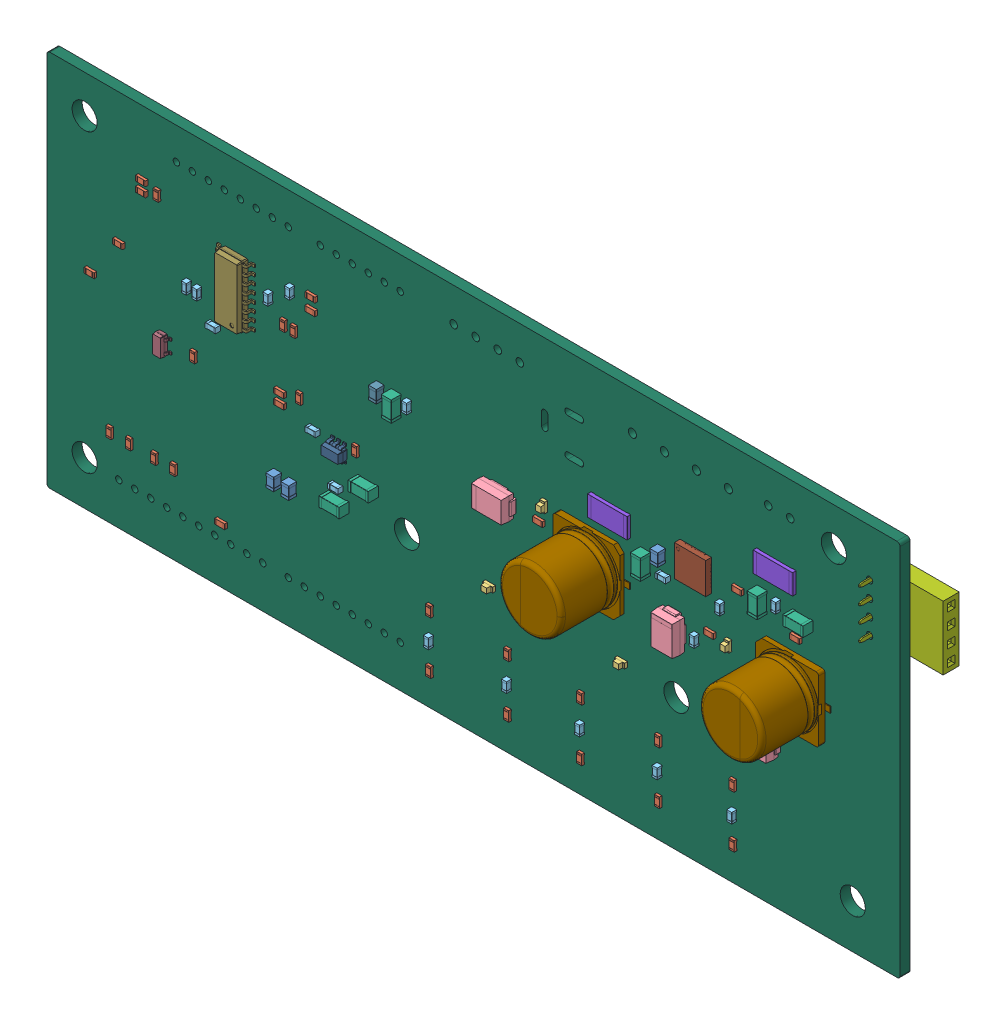
SolidWorks assembly MMTK - For Test Bed v1.5.step, configuration Default. Lengths in mm.
Overall size (140.71 60 14.24).
155 component instances, 15 part files, 0 mates.
Components (placement in the parent):
- C_0805_2012Metric.step-1: C_0805_2012Metric.step [Default] at (39.0906 -40.4144 1.65) x (0 1 0) z (0 0 1) size (2 1.25 1.25)
  - SOLID.step-1: SOLID.step [Default] at origin size (2 1.25 1.25)
- C_0805_2012Metric.step-2: C_0805_2012Metric.step [Default] at (36.6903 -40.4114 1.65) x (0 1 0) z (0 0 1) size (2 1.25 1.25)
  - SOLID.step-1: SOLID.step [Default] at origin size (2 1.25 1.25)
- R_0603_1608Metric.step-1: R_0603_1608Metric.step [Default] at (37.3126 -29.7815 1.65) size (1.6 0.8 0.45)
  - SOLID-0.step-1: SOLID-0.step [Default] at origin size (1.6 0.8 0.45)
- R_0603_1608Metric.step-2: R_0603_1608Metric.step [Default] at (37.3126 -28.2321 1.65) size (1.6 0.8 0.45)
  - SOLID-0.step-1: SOLID-0.step [Default] at origin size (1.6 0.8 0.45)
- R_0603_1608Metric.step-3: R_0603_1608Metric.step [Default] at (78.4097 -25.4 1.65) x (-1 0 0) z (0 0 1) size (1.6 0.8 0.45)
  - SOLID-0.step-1: SOLID-0.step [Default] at origin size (1.6 0.8 0.45)
- LED_0603_1608Metric.step-1: LED_0603_1608Metric.step [Default] at (79.1972 -22.8853 1.65) x (0 1 0) z (0 0 1) size (1.6 0.8 1.1)
  - SOLID-1.step-1: SOLID-1.step [Default] at origin size (1.6 0.8 1.1)
- R_0603_1608Metric.step-4: R_0603_1608Metric.step [Default] at (23.5585 -30.1245 1.65) x (0 1 0) z (0 0 1) size (1.6 0.8 0.45)
  - SOLID-0.step-1: SOLID-0.step [Default] at origin size (1.6 0.8 0.45)
- D_SMB.step-1: D_SMB.step [Default] at (114.046 -37.084 1.65) size (5.3 3.55 2.15)
  - SOLID-2.step-1: SOLID-2.step [Default] at origin size (5.3 3.55 2.15)
- R_0603_1608Metric.step-5: R_0603_1608Metric.step [Default] at (7.2 -26.775 1.65) size (1.6 0.8 0.45)
  - SOLID-0.step-1: SOLID-0.step [Default] at origin size (1.6 0.8 0.45)
- R_0603_1608Metric.step-6: R_0603_1608Metric.step [Default] at (11.7125 -20.525 1.65) x (-1 0 0) z (0 0 1) size (1.6 0.8 0.45)
  - SOLID-0.step-1: SOLID-0.step [Default] at origin size (1.6 0.8 0.45)
- LED_0603_1608Metric.step-2: LED_0603_1608Metric.step [Default] at (70.55 -38.3 1.65) x (-1 0 0) z (0 0 1) size (1.6 0.8 1.1)
  - SOLID-1.step-1: SOLID-1.step [Default] at origin size (1.6 0.8 1.1)
- R_0603_1608Metric.step-7: R_0603_1608Metric.step [Default] at (61.05 -46.3344 1.65) x (0 -1 0) z (0 0 1) size (1.6 0.8 0.45)
  - SOLID-0.step-1: SOLID-0.step [Default] at origin size (1.6 0.8 0.45)
- R_0603_1608Metric.step-8: R_0603_1608Metric.step [Default] at (109.225 -46.2125 1.65) x (0 -1 0) z (0 0 1) size (1.6 0.8 0.45)
  - SOLID-0.step-1: SOLID-0.step [Default] at origin size (1.6 0.8 0.45)
- R_0603_1608Metric.step-9: R_0603_1608Metric.step [Default] at (109.25 -54.4375 1.65) x (0 1 0) z (0 0 1) size (1.6 0.8 0.45)
  - SOLID-0.step-1: SOLID-0.step [Default] at origin size (1.6 0.8 0.45)
- C_0603_1608Metric.step-1: C_0603_1608Metric.step [Default] at (109.225 -50.3875 1.65) x (0 -1 0) z (0 0 1) size (1.6 0.8 0.8)
  - SOLID-3.step-1: SOLID-3.step [Default] at origin size (1.6 0.8 0.8)
- C_1206_3216Metric.step-1: C_1206_3216Metric.step [Default] at (120.145 -18.288 1.65) size (3.2 1.6 1.6)
  - SOLID-4.step-1: SOLID-4.step [Default] at origin size (3.2 1.6 1.6)
- PinSocket_1x04_P2.54mm_Horizontal.step-1: PinSocket_1x04_P2.54mm_Horizontal.step [Default] at (130.682 -7.5 -0.05) x (-1 0 0) z (0 0 -1) size (10.13 10.16 5.84)
  - SOLID-5.step-1: SOLID-5.step [Default] at origin size (10.13 10.16 5.84)
- R_2512_6332Metric.step-1: R_2512_6332Metric.step [Default] at (115.951 -13.589 1.65) size (6.3 3.2 0.6)
  - SOLID-6.step-1: SOLID-6.step [Default] at origin size (6.3 3.2 0.6)
- R_2512_6332Metric.step-2: R_2512_6332Metric.step [Default] at (89.65 -19.02 1.65) x (-1 0 0) z (0 0 1) size (6.3 3.2 0.6)
  - SOLID-6.step-1: SOLID-6.step [Default] at origin size (6.3 3.2 0.6)
- C_1206_3216Metric.step-2: C_1206_3216Metric.step [Default] at (113.665 -18.666 1.65) x (0 -1 0) z (0 0 1) size (3.2 1.6 1.6)
  - SOLID-4.step-1: SOLID-4.step [Default] at origin size (3.2 1.6 1.6)
- C_1206_3216Metric.step-3: C_1206_3216Metric.step [Default] at (95.13 -22.66 1.65) x (0 -1 0) z (0 0 1) size (3.2 1.6 1.6)
  - SOLID-4.step-1: SOLID-4.step [Default] at origin size (3.2 1.6 1.6)
- CP_Elec_10x10.step-1: CP_Elec_10x10.step [Default] at (86.753 -27.27 1.65) x (-1 0 0) z (0 0 1) size (13.47 13.66 10)
  - SOLID-7.step-1: SOLID-7.step [Default] at origin size (13.47 13.66 10)
- CP_Elec_10x10.step-2: CP_Elec_10x10.step [Default] at (118.618 -28.321 1.65) size (13.47 13.66 10)
  - SOLID-7.step-1: SOLID-7.step [Default] at origin size (13.47 13.66 10)
- SOT-23-6.step-1: SOT-23-6.step [Default] at (46.482 -31.58 1.65) x (0 1 0) z (0 0 1) size (2.8 2.9 1.55)
  - SOLID-8.step-1: SOLID-8.step [Default] at origin size (2.8 2.9 1.55)
- QFN-28-1EP_5x5mm_P0.5mm_EP3.35x3.35mm.step-1: QFN-28-1EP_5x5mm_P0.5mm_EP3.35x3.35mm.step [Default] at (103.132 -19.3635 1.65) size (5 5 0.92)
  - SOLID-9.step-1: SOLID-9.step [Default] at origin size (5 5 0.92)
- SOIC-16_3.9x9.9mm_P1.27mm.step-1: SOIC-16_3.9x9.9mm_P1.27mm.step [Default] at (30.226 -17.399 1.65) x (-1 0 0) z (0 0 1) size (6 9.9 1.75)
  - SOLID-10.step-1: SOLID-10.step [Default] at origin size (6 9.9 1.75)
- R_0603_1608Metric.step-10: R_0603_1608Metric.step [Default] at (10.2616 -47.1932 1.65) x (0 -1 0) z (0 0 1) size (1.6 0.8 0.45)
  - SOLID-0.step-1: SOLID-0.step [Default] at origin size (1.6 0.8 0.45)
- R_0603_1608Metric.step-11: R_0603_1608Metric.step [Default] at (13.3604 -47.1932 1.65) x (0 -1 0) z (0 0 1) size (1.6 0.8 0.45)
  - SOLID-0.step-1: SOLID-0.step [Default] at origin size (1.6 0.8 0.45)
- R_0603_1608Metric.step-12: R_0603_1608Metric.step [Default] at (17.3736 -47.1932 1.65) x (0 -1 0) z (0 0 1) size (1.6 0.8 0.45)
  - SOLID-0.step-1: SOLID-0.step [Default] at origin size (1.6 0.8 0.45)
- R_0603_1608Metric.step-13: R_0603_1608Metric.step [Default] at (20.4216 -47.1932 1.65) x (0 -1 0) z (0 0 1) size (1.6 0.8 0.45)
  - SOLID-0.step-1: SOLID-0.step [Default] at origin size (1.6 0.8 0.45)
- R_0603_1608Metric.step-14: R_0603_1608Metric.step [Default] at (61.05 -54.663 1.65) x (0 1 0) z (0 0 1) size (1.6 0.8 0.45)
  - SOLID-0.step-1: SOLID-0.step [Default] at origin size (1.6 0.8 0.45)
- R_0603_1608Metric.step-15: R_0603_1608Metric.step [Default] at (85.05 -54.6521 1.65) x (0 1 0) z (0 0 1) size (1.6 0.8 0.45)
  - SOLID-0.step-1: SOLID-0.step [Default] at origin size (1.6 0.8 0.45)
- R_0603_1608Metric.step-16: R_0603_1608Metric.step [Default] at (85.05 -46.3234 1.65) x (0 -1 0) z (0 0 1) size (1.6 0.8 0.45)
  - SOLID-0.step-1: SOLID-0.step [Default] at origin size (1.6 0.8 0.45)
- R_0603_1608Metric.step-17: R_0603_1608Metric.step [Default] at (73.45 -54.47 1.65) x (0 1 0) z (0 0 1) size (1.6 0.8 0.45)
  - SOLID-0.step-1: SOLID-0.step [Default] at origin size (1.6 0.8 0.45)
- R_0603_1608Metric.step-18: R_0603_1608Metric.step [Default] at (97.375 -54.3841 1.65) x (0 1 0) z (0 0 1) size (1.6 0.8 0.45)
  - SOLID-0.step-1: SOLID-0.step [Default] at origin size (1.6 0.8 0.45)
- R_0603_1608Metric.step-19: R_0603_1608Metric.step [Default] at (73.45 -46.1414 1.65) x (0 -1 0) z (0 0 1) size (1.6 0.8 0.45)
  - SOLID-0.step-1: SOLID-0.step [Default] at origin size (1.6 0.8 0.45)
- R_0603_1608Metric.step-20: R_0603_1608Metric.step [Default] at (97.375 -46.0555 1.65) x (0 -1 0) z (0 0 1) size (1.6 0.8 0.45)
  - SOLID-0.step-1: SOLID-0.step [Default] at origin size (1.6 0.8 0.45)
- R_0603_1608Metric.step-21: R_0603_1608Metric.step [Default] at (105.5371 -27.2288 1.65) x (-1 0 0) z (0 0 1) size (1.6 0.8 0.45)
  - SOLID-0.step-1: SOLID-0.step [Default] at origin size (1.6 0.8 0.45)
- R_0603_1608Metric.step-22: R_0603_1608Metric.step [Default] at (119.2275 -21.082 1.65) x (-1 0 0) z (0 0 1) size (1.6 0.8 0.45)
  - SOLID-0.step-1: SOLID-0.step [Default] at origin size (1.6 0.8 0.45)
- R_0603_1608Metric.step-23: R_0603_1608Metric.step [Default] at (27.94 -50.927 1.65) size (1.6 0.8 0.45)
  - SOLID-0.step-1: SOLID-0.step [Default] at origin size (1.6 0.8 0.45)
- R_0603_1608Metric.step-24: R_0603_1608Metric.step [Default] at (109.982 -19.05 1.65) size (1.6 0.8 0.45)
  - SOLID-0.step-1: SOLID-0.step [Default] at origin size (1.6 0.8 0.45)
- R_0603_1608Metric.step-25: R_0603_1608Metric.step [Default] at (37.846 -18.669 1.65) x (0 -1 0) z (0 0 1) size (1.6 0.8 0.45)
  - SOLID-0.step-1: SOLID-0.step [Default] at origin size (1.6 0.8 0.45)
- R_0603_1608Metric.step-26: R_0603_1608Metric.step [Default] at (39.497 -18.669 1.65) x (0 1 0) z (0 0 1) size (1.6 0.8 0.45)
  - SOLID-0.step-1: SOLID-0.step [Default] at origin size (1.6 0.8 0.45)
- R_0603_1608Metric.step-27: R_0603_1608Metric.step [Default] at (42.2655 -14.478 1.65) size (1.6 0.8 0.45)
  - SOLID-0.step-1: SOLID-0.step [Default] at origin size (1.6 0.8 0.45)
- R_0603_1608Metric.step-28: R_0603_1608Metric.step [Default] at (40.3733 -27.4447 1.65) x (0 1 0) z (0 0 1) size (1.6 0.8 0.45)
  - SOLID-0.step-1: SOLID-0.step [Default] at origin size (1.6 0.8 0.45)
- R_0603_1608Metric.step-29: R_0603_1608Metric.step [Default] at (42.291 -12.573 1.65) size (1.6 0.8 0.45)
  - SOLID-0.step-1: SOLID-0.step [Default] at origin size (1.6 0.8 0.45)
- R_0603_1608Metric.step-30: R_0603_1608Metric.step [Default] at (49.276 -30.226 1.65) x (0 1 0) z (0 0 1) size (1.6 0.8 0.45)
  - SOLID-0.step-1: SOLID-0.step [Default] at origin size (1.6 0.8 0.45)
- R_0603_1608Metric.step-31: R_0603_1608Metric.step [Default] at (15.367 -10.033 1.65) size (1.6 0.8 0.45)
  - SOLID-0.step-1: SOLID-0.step [Default] at origin size (1.6 0.8 0.45)
- R_0603_1608Metric.step-32: R_0603_1608Metric.step [Default] at (17.78 -10.795 1.65) x (0 1 0) z (0 0 1) size (1.6 0.8 0.45)
  - SOLID-0.step-1: SOLID-0.step [Default] at origin size (1.6 0.8 0.45)
- R_0603_1608Metric.step-33: R_0603_1608Metric.step [Default] at (15.367 -11.557 1.65) size (1.6 0.8 0.45)
  - SOLID-0.step-1: SOLID-0.step [Default] at origin size (1.6 0.8 0.45)
- SOT-23.step-1: SOT-23.step [Default] at (18.669 -30.734 1.65) x (-1 0 0) z (0 0 1) size (2.5 3 1.2)
  - SOLID-11.step-1: SOLID-11.step [Default] at origin size (2.5 3 1.2)
- L_0805_2012Metric.step-1: L_0805_2012Metric.step [Default] at (53.009 -20.194 1.65) x (0 1 0) z (0 0 1) size (2 1.25 1.25)
  - SOLID-12.step-1: SOLID-12.step [Default] at origin size (2 1.25 1.25)
- LED_0603_1608Metric.step-3: LED_0603_1608Metric.step [Default] at (91.5 -38.275 1.65) x (-1 0 0) z (0 0 1) size (1.6 0.8 1.1)
  - SOLID-1.step-1: SOLID-1.step [Default] at origin size (1.6 0.8 1.1)
- LED_0603_1608Metric.step-4: LED_0603_1608Metric.step [Default] at (81.025 -38.3 1.65) x (-1 0 0) z (0 0 1) size (1.6 0.8 1.1)
  - SOLID-1.step-1: SOLID-1.step [Default] at origin size (1.6 0.8 1.1)
- LED_0603_1608Metric.step-5: LED_0603_1608Metric.step [Default] at (108.458 -27.432 1.65) x (0 1 0) z (0 0 1) size (1.6 0.8 1.1)
  - SOLID-1.step-1: SOLID-1.step [Default] at origin size (1.6 0.8 1.1)
- D_SMB.step-2: D_SMB.step [Default] at (99.822 -29.464 1.65) x (0 -1 0) z (0 0 1) size (5.3 3.55 2.15)
  - SOLID-2.step-1: SOLID-2.step [Default] at origin size (5.3 3.55 2.15)
- D_SMB.step-3: D_SMB.step [Default] at (72 -25.32 1.65) size (5.3 3.55 2.15)
  - SOLID-2.step-1: SOLID-2.step [Default] at origin size (5.3 3.55 2.15)
- C_0603_1608Metric.step-2: C_0603_1608Metric.step [Default] at (61.05 -50.4987 1.65) x (0 -1 0) z (0 0 1) size (1.6 0.8 0.8)
  - SOLID-3.step-1: SOLID-3.step [Default] at origin size (1.6 0.8 0.8)
- C_0603_1608Metric.step-3: C_0603_1608Metric.step [Default] at (85.05 -50.4878 1.65) x (0 -1 0) z (0 0 1) size (1.6 0.8 0.8)
  - SOLID-3.step-1: SOLID-3.step [Default] at origin size (1.6 0.8 0.8)
- C_0603_1608Metric.step-4: C_0603_1608Metric.step [Default] at (73.45 -50.3057 1.65) x (0 -1 0) z (0 0 1) size (1.6 0.8 0.8)
  - SOLID-3.step-1: SOLID-3.step [Default] at origin size (1.6 0.8 0.8)
- C_0603_1608Metric.step-5: C_0603_1608Metric.step [Default] at (97.375 -50.2198 1.65) x (0 -1 0) z (0 0 1) size (1.6 0.8 0.8)
  - SOLID-3.step-1: SOLID-3.step [Default] at origin size (1.6 0.8 0.8)
- C_0603_1608Metric.step-6: C_0603_1608Metric.step [Default] at (103.251 -29.21 1.65) x (0 -1 0) z (0 0 1) size (1.6 0.8 0.8)
  - SOLID-3.step-1: SOLID-3.step [Default] at origin size (1.6 0.8 0.8)
- C_0603_1608Metric.step-7: C_0603_1608Metric.step [Default] at (98.2726 -23.0505 1.65) size (1.6 0.8 0.8)
  - SOLID-3.step-1: SOLID-3.step [Default] at origin size (1.6 0.8 0.8)
- C_0805_2012Metric.step-3: C_0805_2012Metric.step [Default] at (97.68 -20.3275 1.65) x (0 -1 0) z (0 0 1) size (2 1.25 1.25)
  - SOLID.step-1: SOLID.step [Default] at origin size (2 1.25 1.25)
- C_0603_1608Metric.step-8: C_0603_1608Metric.step [Default] at (107.315 -22.733 1.65) x (0 -1 0) z (0 0 1) size (1.6 0.8 0.8)
  - SOLID-3.step-1: SOLID-3.step [Default] at origin size (1.6 0.8 0.8)
- C_0603_1608Metric.step-9: C_0603_1608Metric.step [Default] at (116.205 -18.034 1.65) x (0 -1 0) z (0 0 1) size (1.6 0.8 0.8)
  - SOLID-3.step-1: SOLID-3.step [Default] at origin size (1.6 0.8 0.8)
- C_0603_1608Metric.step-10: C_0603_1608Metric.step [Default] at (26.797 -24.384 1.65) x (-1 0 0) z (0 0 1) size (1.6 0.8 0.8)
  - SOLID-3.step-1: SOLID-3.step [Default] at origin size (1.6 0.8 0.8)
- C_0603_1608Metric.step-11: C_0603_1608Metric.step [Default] at (24.257 -20.955 1.65) x (0 1 0) z (0 0 1) size (1.6 0.8 0.8)
  - SOLID-3.step-1: SOLID-3.step [Default] at origin size (1.6 0.8 0.8)
- C_0603_1608Metric.step-12: C_0603_1608Metric.step [Default] at (22.606 -20.955 1.65) x (0 1 0) z (0 0 1) size (1.6 0.8 0.8)
  - SOLID-3.step-1: SOLID-3.step [Default] at origin size (1.6 0.8 0.8)
- C_0603_1608Metric.step-13: C_0603_1608Metric.step [Default] at (35.56 -16.002 1.65) x (0 -1 0) z (0 0 1) size (1.6 0.8 0.8)
  - SOLID-3.step-1: SOLID-3.step [Default] at origin size (1.6 0.8 0.8)
- C_0603_1608Metric.step-14: C_0603_1608Metric.step [Default] at (57.581 -19.94 1.65) x (0 -1 0) z (0 0 1) size (1.6 0.8 0.8)
  - SOLID-3.step-1: SOLID-3.step [Default] at origin size (1.6 0.8 0.8)
- C_0603_1608Metric.step-15: C_0603_1608Metric.step [Default] at (42.672 -30.734 1.65) size (1.6 0.8 0.8)
  - SOLID-3.step-1: SOLID-3.step [Default] at origin size (1.6 0.8 0.8)
- C_0603_1608Metric.step-16: C_0603_1608Metric.step [Default] at (38.989 -13.4365 1.65) x (0 -1 0) z (0 0 1) size (1.6 0.8 0.8)
  - SOLID-3.step-1: SOLID-3.step [Default] at origin size (1.6 0.8 0.8)
- C_0603_1608Metric.step-17: C_0603_1608Metric.step [Default] at (46.2661 -36.7411 1.65) x (-1 0 0) z (0 0 1) size (1.6 0.8 0.8)
  - SOLID-3.step-1: SOLID-3.step [Default] at origin size (1.6 0.8 0.8)
- C_1206_3216Metric.step-4: C_1206_3216Metric.step [Default] at (55.549 -20.702 1.65) x (0 -1 0) z (0 0 1) size (3.2 1.6 1.6)
  - SOLID-4.step-1: SOLID-4.step [Default] at origin size (3.2 1.6 1.6)
- C_1206_3216Metric.step-5: C_1206_3216Metric.step [Default] at (46.4566 -38.8112 1.65) x (-1 0 0) z (0 0 1) size (3.2 1.6 1.6)
  - SOLID-4.step-1: SOLID-4.step [Default] at origin size (3.2 1.6 1.6)
- C_1206_3216Metric.step-6: C_1206_3216Metric.step [Default] at (51.0921 -34.3154 1.65) size (3.2 1.6 1.6)
  - SOLID-4.step-1: SOLID-4.step [Default] at origin size (3.2 1.6 1.6)
- COMPOUND.step-1: COMPOUND.step [Default] at origin size (135.51 60 1.6)
